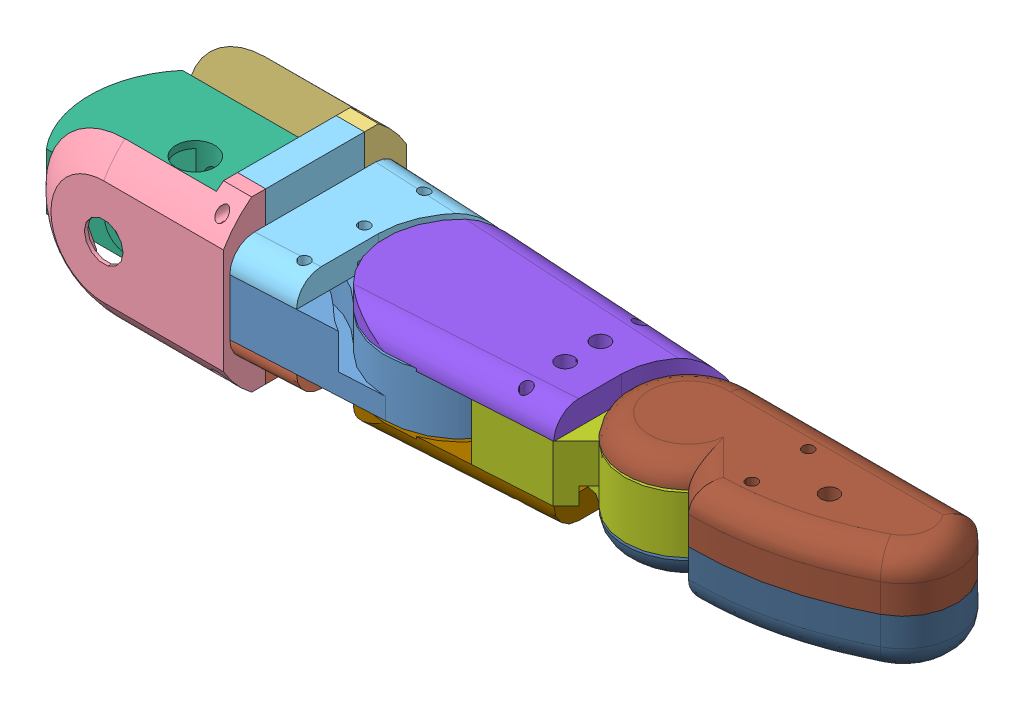
SolidWorks assembly thumb-assembly, configuration Default. Lengths in mm.
Overall size (120 24 26).
14 component instances, 11 part files, 4 mates.
Components (placement in the parent):
- thumbP-assembly-1: thumbP-assembly [Default] at (13.477 -34.8052 50.0565) size (64 24 26)
  - thumbP-middle-1: thumbP-middle [Default] at (-35.7341 29.3306 13.9435) size (36 8 24.21)
  - thumbP-bottom-1: thumbP-bottom [Default] at (-35.7341 29.3306 13.9435) size (21.17 8.41 24.21)
  - thumbP-left-1: thumbP-left [Default] at (-35.7341 33.3306 0.9435) size (28.18 24 6)
  - thumbP-right-1: thumbP-right [Default] at (-35.7341 33.3306 26.9435) size (28.18 24 6)
  - thumbP-top-1: thumbP-top [Default] at (-35.7341 37.3306 13.9435) size (21.17 8.42 24.21)
  - thumbP-joint-1: thumbP-joint [Default] at (-54.1244 33.3306 4.2935) size (26 8 22.55)
- thumbM-assembly-1: thumbM-assembly [Default] at (41.515 -34.1319 46.5512) x (1 0 0) z (0 -1 0) size (52 22 16.39)
  - thumbM-middle-2: thumbM-middle [Default] at (-25.772 17.4488 -36.6574) size (36.9 21.02 8)
  - thumbM-left-2: thumbM-left [Default] at (6.228 17.4488 -40.1574) size (40.91 22 6.45)
  - thumbM-right-2: thumbM-right [Default] at (6.228 17.4488 -28.6574) size (40.87 22 7.09)
- thumbD-assembly-1: thumbD-assembly [Default] at (88.8622 23.9583 80.6139) x (1 0 0) z (0 1 0) size (44 19.23 15.7)
  - thumbD-left-1: thumbD-left [Default] at (-41.1193 16.6139 -32.9328) size (44 19.23 7.85)
  - thumbD-right-1: thumbD-right [Default] at (-41.1193 16.6139 -25.4328) size (44 19.15 7.85)
Mates (geometry in assembly coordinates):
- Concentric1: concentric aligned: cylinder of thumbM-assembly-1/thumbM-middle-2 through (47.7429 -5.4745 64) axis (0 1 0) radius 2.75; cylinder of thumbD-assembly-1/thumbD-right-1 through (47.7429 0.6255 64) axis (0 1 0) radius 2.5
- Distance1: distance = 0.1 mm anti-aligned: plane of thumbD-assembly-1/thumbD-right-1 through (47.7429 2.6255 64) normal (0 -1 0); plane of thumbM-assembly-1/thumbM-middle-2 through (15.7429 2.5255 64) normal (0 1 0)
- Concentric2: concentric aligned: cylinder of thumbP-assembly-1/thumbP-middle-1 through (15.7429 -1.4745 64) axis (0 -1 0) radius 7.5; cylinder of thumbM-assembly-1/thumbM-right-2 through (15.7429 -2.5745 64) axis (0 -1 0) radius 7
- Distance2: distance = 0.1 mm anti-aligned: plane of thumbM-assembly-1/thumbM-right-2 through (15.7429 -5.5745 64) normal (0 1 0); plane of thumbP-assembly-1/thumbP-middle-1 through (-22.2571 -5.4745 64) normal (0 -1 0)
